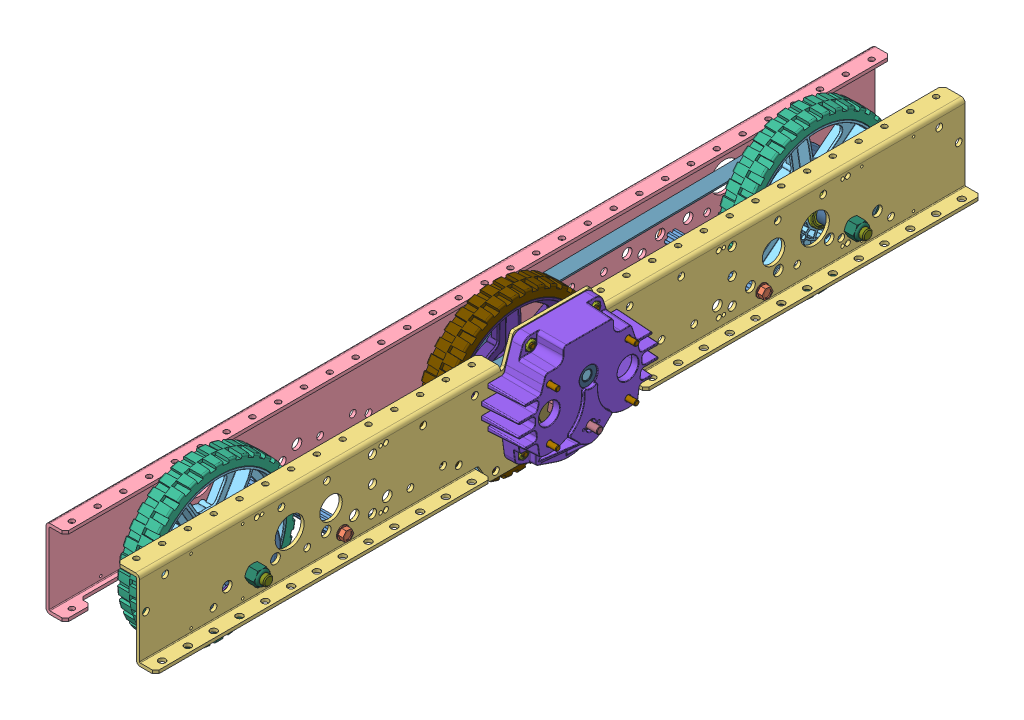
SolidWorks assembly AM14U3Long_Half, configuration Default. Lengths in mm.
Overall size (145.24 219.18 812.8).
91 component instances, 28 part files, 6 mates.
Components (placement in the parent):
- AM14U3Long_Frame_Half-1: AM14U3Long_Frame_Half [Default] at (0 136.144 -762.762) size (113.54 116.33 812.8)
  - 500Churro_3.375-2: 500Churro_3.375 [Default] at (-501.65 -66.929 562.737) x (0 0 1) z (-1 0 0) size (14.66 12.7 85.72)
  - 500Churro_3.375-4: 500Churro_3.375 [Default] at (-501.65 -66.929 149.987) x (0 0 1) z (-1 0 0) size (14.66 12.7 85.72)
  - ThreadRollingScrew_0.25-20x0.75_FHTS 0.25-20-G-0.75-C-1: ThreadRollingScrew_0.25-20x0.75_FHTS 0.25-20-G-0.75-C [Default] at (-498.475 -66.929 562.737) x (-1 0 0) z (0 0.924225 0.381849) size (24.64 12.19 12.19)
  - ThreadRollingScrew_0.25-20x0.75_FHTS 0.25-20-G-0.75-C-4: ThreadRollingScrew_0.25-20x0.75_FHTS 0.25-20-G-0.75-C [Default] at (-498.475 -66.929 149.987) x (-1 0 0) z (0 0.924225 0.381849) size (24.64 12.19 12.19)
  - ThreadRollingScrew_0.25-20x0.75_FHTS 0.25-20-G-0.75-C-5: ThreadRollingScrew_0.25-20x0.75_FHTS 0.25-20-G-0.75-C [Default] at (-590.55 -66.929 562.737) size (24.64 12.19 12.19)
  - ThreadRollingScrew_0.25-20x0.75_FHTS 0.25-20-G-0.75-C-7: ThreadRollingScrew_0.25-20x0.75_FHTS 0.25-20-G-0.75-C [Default] at (-590.55 -66.929 149.987) size (24.64 12.19 12.19)
  - AM14U3InnerPlate_Long-1: AM14U3InnerPlate_Long [Default] at (-501.65 -77.216 762.762) x (0 0 -1) z (0 -1 0) size (812.8 38.1 116.33)
  - AM14U3OuterPlate_Long_DefaultSM-FLAT-PATTERN-1: AM14U3OuterPlate_Long_DefaultSM-FLAT-PATTERN [Default] at (-587.375 -77.216 -50.038) x (0 0 1) z (0 -1 0) size (812.8 19.05 77.72)
- ToughboxMini-1: ToughboxMini [Default] at (-549.0167 66.1299 -315.2992) x (0 0.001296 0.999999) z (-1 0 0) size (140.05 118.73 142.29)
  - TBMiniSmallHexShaft-1: TBMiniSmallHexShaft [Default] at (-127.8104 29.3671 -52.3959) x (-0.59657 -0.802561 0) z (-0.802561 0.59657 0) size (11 38.23 9.52)
  - Bearing_FR6ZZ-1: Bearing_FR6ZZ [Default] at (-96.247 60.278 -52.5991) x (-0.893862 0.448342 0) z (0 0 1) size (24.69 24.69 7.16)
  - NylockNut_10-32-1: NylockNut_10-32 [Default] at (-129.8464 -8.0737 -56.3837) x (0.501678 0.865055 0) z (0 0 -1) size (9.53 11 5.96)
  - NylockNut_10-32-2: NylockNut_10-32 [Default] at (-59.2462 80.7349 -56.3837) x (0.999999 -0.001296 0) z (0 0 -1) size (9.53 11 5.96)
  - NylockNut_10-32-3: NylockNut_10-32 [Default] at (-122.7461 80.8172 -56.3837) x (0.500567 0.865698 0) z (0 0 -1) size (9.53 11 5.96)
  - NylockNut_10-32-4: NylockNut_10-32 [Default] at (-52.3764 -8.1741 -56.3837) x (-0.501678 -0.865055 0) z (0 0 -1) size (9.53 11 5.96)
  - TBMiniHousing-1: TBMiniHousing [Default] at (-91.0876 10.1882 -86.3557) x (0.999999 -0.001296 0) z (0 0 1) size (139.9 118.55 41.62)
  - Screw_SHCS_10-32x0.625-1: Screw_SHCS_10-32x0.625 [Default] at (-52.2832 63.7078 -74.4685) x (-0.564778 -0.825243 0) z (-0.825243 0.564778 0) size (7.82 20.65 7.82)
  - Screw_SHCS_10-32x0.625-2: Screw_SHCS_10-32x0.625 [Default] at (-122.7461 80.8172 -42.5915) x (0.507484 -0.861661 0) z (-0.861661 -0.507484 0) size (7.82 20.65 7.82)
  - Screw_SHCS_10-32x0.625-3: Screw_SHCS_10-32x0.625 [Default] at (-52.3764 -8.1741 -42.5915) x (0.507484 -0.861661 0) z (-0.861661 -0.507484 0) size (7.82 20.65 7.82)
  - Screw_SHCS_10-32x0.625-4: Screw_SHCS_10-32x0.625 [Default] at (-129.8464 -8.0737 -42.5915) x (0.507484 -0.861661 0) z (-0.861661 -0.507484 0) size (7.82 20.65 7.82)
  - Screw_SHCS_10-32x0.625-5: Screw_SHCS_10-32x0.625 [Default] at (-59.2462 80.7349 -42.5915) x (0.740711 -0.671824 0) z (-0.671824 -0.740711 0) size (7.82 20.65 7.82)
  - Screw_SHCS_10-32x0.625-6: Screw_SHCS_10-32x0.625 [Default] at (-52.3491 12.9079 -74.4685) x (-0.564778 -0.825243 0) z (-0.825243 0.564778 0) size (7.82 20.65 7.82)
  - Screw_SHCS_10-32x0.625-7: Screw_SHCS_10-32x0.625 [Default] at (-129.7532 63.8083 -74.4685) x (-0.966277 -0.257503 0) z (-0.257503 0.966277 0) size (7.82 20.65 7.82)
  - Screw_SHCS_10-32x0.625-8: Screw_SHCS_10-32x0.625 [Default] at (-129.819 13.0083 -74.4685) x (-0.99652 0.083357 0) z (0.083357 0.99652 0) size (7.82 20.65 7.82)
  - Bearing_R6ZZ-1: Bearing_R6ZZ [Default] at (-91.0349 50.9043 -84.8317) x (0.958138 -0.286306 0) z (0 0 1) size (22.23 22.23 7.11)
  - Bearing_R6ZZ-2: Bearing_R6ZZ [Default] at (-91.0876 10.1882 -84.8317) x (-0.661529 0.74992 0) z (0 0 1) size (22.23 22.23 7.11)
  - ExternalKlipring-1: ExternalKlipring [Default] at (-91.0876 10.1882 -64.4355) x (0.996411 -0.084651 0) z (0 0 1) size (19.07 20.96 1.27)
  - Bearing_Hex_FR8ZZ-1: Bearing_Hex_FR8ZZ [Default] at (-91.0876 10.1882 -44.6717) x (0.188693 -0.982036 0) z (0 0 -1) size (31.12 31.12 7.93)
  - TBMiniHexOutputShaft-1: TBMiniHexOutputShaft [Default] at (-100.2289 -30.5762 -52.3197) x (0.188693 -0.982036 0) z (-0.982036 -0.188693 0) size (14.66 142.29 12.7)
- Bearing_Hex_FR8ZZ-1: Bearing_Hex_FR8ZZ [Default] at (-593.7783 76.2 -406.4) x (0 0.32638 -0.945239) z (1 0 0) size (31.12 31.12 7.93)
- Belt_15mm_Long-1: Belt_15mm_Long [Default] at (-511.5261 79.756 -111.3496) x (0 -0.012051 -0.999927) z (0 0.999927 -0.012051) size (368.15 15 73.08)
- Belt_15mm_Long-2: Belt_15mm_Long [Default] at (-576.9127 76.2 -406.4) x (0 0.012051 -0.999927) z (0 -0.999927 -0.012051) size (368.15 15 73.08)
- NylockNut_0.375-16_91831A127-1: NylockNut_0.375-16_91831A127 [Default] at (-498.475 79.756 -701.4504) x (0 -1 0) z (0 0 1) size (14.29 12 16.5)
- NylockNut_0.375-16_91831A127-2: NylockNut_0.375-16_91831A127 [Default] at (-498.475 79.7563 -111.3496) x (0 -1 0) z (0 0 1) size (14.29 12 16.5)
- HHSBolt_0.375-16x4.25_HFBOLT 0.375-16x2.5x1-C-1: HHSBolt_0.375-16x4.25_HFBOLT 0.375-16x2.5x1-C [Default] at (-596.7222 79.756 -111.3496) size (114.12 16.48 14.27)
- HHSBolt_0.375-16x4.25_HFBOLT 0.375-16x2.5x1-C-2: HHSBolt_0.375-16x4.25_HFBOLT 0.375-16x2.5x1-C [Default] at (-596.7222 79.756 -701.4504) x (1 0 0) z (0 -0.203423 -0.979091) size (114.12 16.48 14.27)
- Wheel_6inHiGrip_Center-1: Wheel_6inHiGrip_Center [Default] at (-513.0653 208.3565 -483.6317) x (-1 0 0) z (0 -0.493281 0.86987) size (81.42 191.55 191.55)
  - Wheel_6inHiGrip-1: Wheel_6inHiGrip [Default] at (83.7987 67.439 110.9939) size (34.93 191.55 191.55)
    - Wheel_6inHiGrip_Wheel-1: Wheel_6inHiGrip_Wheel [Default] at (-52.6446 9.4231 21.378) size (34.93 132.08 132.08)
    - Wheel_6inHiGrip_Tread-1: Wheel_6inHiGrip_Tread [Default] at (-65.3446 9.4231 21.378) x (0 -0.304368 -0.952555) z (1 0 0) size (152.4 152.4 25.58)
  - HalfPulley_42t5mm-1: HalfPulley_42t5mm [Default] at (47.6006 76.862 132.3719) x (1 0 0) z (0 -0.5 0.866025) size (13 74.23 74.23)
  - HalfPulley_42t5mm-2: HalfPulley_42t5mm [Default] at (64.263 76.862 132.3719) x (-1 0 0) z (0 -0.499927 0.866067) size (13 74.23 74.23)
  - ThreadFormingScrew_10-24x1.25_93882A213-1: ThreadFormingScrew_10-24x1.25_93882A213 [Default] at (63.247 76.8605 108.5602) x (0 0.953802 -0.300437) z (1 0 0) size (10.52 10.52 35.59)
  - ThreadFormingScrew_10-24x1.25_93882A213-2: ThreadFormingScrew_10-24x1.25_93882A213 [Default] at (63.247 97.4833 120.4656) x (0 0.953802 -0.300437) z (1 0 0) size (10.52 10.52 35.59)
  - ThreadFormingScrew_10-24x1.25_93882A213-3: ThreadFormingScrew_10-24x1.25_93882A213 [Default] at (63.247 56.2398 144.2799) x (0 0.953802 -0.300437) z (1 0 0) size (10.52 10.52 35.59)
  - ThreadFormingScrew_10-24x1.25_93882A213-4: ThreadFormingScrew_10-24x1.25_93882A213 [Default] at (63.247 76.8625 156.1852) x (0 -0.013882 -0.999904) z (1 0 0) size (10.52 10.52 35.59)
  - ThreadFormingScrew_10-24x1.25_93882A213-5: ThreadFormingScrew_10-24x1.25_93882A213 [Default] at (63.247 97.4843 144.2781) x (0 -0.733065 -0.680158) z (1 0 0) size (10.52 10.52 35.59)
  - ThreadFormingScrew_10-24x1.25_93882A213-6: ThreadFormingScrew_10-24x1.25_93882A213 [Default] at (63.247 56.2388 120.4674) x (0 0.407306 -0.913292) z (1 0 0) size (10.52 10.52 35.59)
  - HalfPulley_42t5mm-3: HalfPulley_42t5mm [Default] at (-1.9548 76.862 132.3719) x (1 0 0) z (0 -1 -0.000063) size (13 74.23 74.23)
  - HalfPulley_42t5mm-4: HalfPulley_42t5mm [Default] at (14.7076 76.862 132.3719) x (-1 0 0) z (0 -1 0.000021) size (13 74.23 74.23)
  - HexHub_500EX-1: HexHub_500EX [Default] at (-8.3048 76.862 132.3719) x (0 -0.866025 -0.5) z (0 -0.5 0.866025) size (55.37 25.4 51.33)
  - ThreadFormingScrew_10-24x1.25_93882A213-7: ThreadFormingScrew_10-24x1.25_93882A213 [Default] at (-5.2568 97.4843 120.4656) x (0 -0.953802 0.300437) z (-1 0 0) size (10.52 10.52 35.59)
  - ThreadFormingScrew_10-24x1.25_93882A213-8: ThreadFormingScrew_10-24x1.25_93882A213 [Default] at (-5.2568 76.862 108.5594) x (0 -0.953802 0.300437) z (-1 0 0) size (10.52 10.52 35.59)
  - ThreadFormingScrew_10-24x1.25_93882A213-9: ThreadFormingScrew_10-24x1.25_93882A213 [Default] at (-5.2568 56.2398 120.4656) x (0 -0.953802 0.300437) z (-1 0 0) size (10.52 10.52 35.59)
  - ThreadFormingScrew_10-24x1.25_93882A213-10: ThreadFormingScrew_10-24x1.25_93882A213 [Default] at (-5.2568 97.4843 144.2781) x (0 -0.192002 -0.981394) z (-1 0 0) size (10.52 10.52 35.59)
  - ThreadFormingScrew_10-24x1.25_93882A213-11: ThreadFormingScrew_10-24x1.25_93882A213 [Default] at (-5.2568 56.2398 144.2781) x (0 -0.986288 0.16503) z (-1 0 0) size (10.52 10.52 35.59)
  - ThreadFormingScrew_10-24x1.25_93882A213-12: ThreadFormingScrew_10-24x1.25_93882A213 [Default] at (-5.2568 76.862 156.1844) x (0 -0.150217 -0.988653) z (-1 0 0) size (10.52 10.52 35.59)
  - Spacer_Hex_0.57x0.5-1: Spacer_Hex_0.57x0.5 [Default] at (57.8495 76.862 132.3719) x (0 -0.866025 -0.5) z (0 -0.5 0.866025) size (28.55 14.48 28.55)
- 6 HiGrip with bearings, pulleys and spacers-1: 6 HiGrip with bearings, pulleys and spacers [Default] at (-574.9579 3.6159 21.4388) x (1 0 0) z (0 0.865776 -0.500432) size (85.56 152.4 152.4)
  - 6 HiGrip Wheel Assembly Rev II-1: 6 HiGrip Wheel Assembly Rev II [Default] at (83.7987 67.439 110.9939) size (34.93 152.4 152.4)
    - 6 wheel Rev 4-1: 6 wheel Rev 4 [Default] at (-52.6446 9.4231 21.378) size (34.93 132.08 132.08)
    - 6 wheel tread II-1: 6 wheel tread II [Default] at (-65.3446 9.4231 21.378) x (0 0 -1) z (1 0 0) size (152.4 152.4 25.58)
  - HalfPulley_42t5mm-1: HalfPulley_42t5mm [Default] at (47.6006 76.862 132.3719) x (1 0 0) z (0 -0.5 0.866025) size (13 74.23 74.23)
  - HalfPulley_42t5mm-2: HalfPulley_42t5mm [Default] at (64.263 76.862 132.3719) x (-1 0 0) z (0 -0.499927 0.866067) size (13 74.23 74.23)
  - Bearing_1614ZZ-1: Bearing_1614ZZ [Default] at (62.612 76.862 132.3719) x (0 0.904908 -0.425608) z (-1 0 0) size (28.58 28.58 9.53)
  - Bearing_1614ZZ-2: Bearing_1614ZZ [Default] at (15.2791 76.862 132.3719) x (0 0.960548 -0.278115) z (1 0 0) size (28.58 28.58 9.53)
  - Washer_5-16-1: Washer_5-16 [Default] at (63.247 76.8605 108.5602) x (0 -0.624545 -0.780988) z (1 0 0) size (17.53 17.53 1.47)
  - Washer_5-16-2: Washer_5-16 [Default] at (63.247 97.4833 120.4656) x (0 -0.995817 0.091369) z (1 0 0) size (17.53 17.53 1.47)
  - Washer_5-16-3: Washer_5-16 [Default] at (63.247 56.2398 144.2799) x (0 0.546149 0.837688) z (1 0 0) size (17.53 17.53 1.47)
  - Washer_5-16-4: Washer_5-16 [Default] at (63.247 76.8625 156.1852) x (0 0.642695 -0.766122) z (1 0 0) size (17.53 17.53 1.47)
  - Washer_5-16-5: Washer_5-16 [Default] at (63.247 97.4843 144.2781) x (0 0.936259 -0.351311) z (1 0 0) size (17.53 17.53 1.47)
  - Washer_5-16-6: Washer_5-16 [Default] at (63.247 56.2388 120.4674) x (0 -0.160557 -0.987027) z (1 0 0) size (17.53 17.53 1.47)
  - Spacer_0.28x0.382-1: Spacer_0.28x0.382 [Default] at (74.4865 76.862 132.3719) x (0 -0.996837 -0.07947) z (-1 0 0) size (13.16 13.16 7.11)
  - Spacer_0.85x0.38-1: Spacer_0.85x0.38 [Default] at (-11.0734 76.862 132.3719) x (0 0.960548 -0.278115) z (1 0 0) size (19.05 19.05 21.59)
- 6 HiGrip with bearings, pulleys and spacers-2: 6 HiGrip with bearings, pulleys and spacers [Default] at (-513.4809 -62.9554 -646.1011) x (-1 0 0) z (0 0.624698 -0.780867) size (85.56 152.4 152.4)
  - 6 HiGrip Wheel Assembly Rev II-1: 6 HiGrip Wheel Assembly Rev II [Default] at (83.7987 67.439 110.9939) size (34.93 152.4 152.4)
    - 6 wheel Rev 4-1: 6 wheel Rev 4 [Default] at (-52.6446 9.4231 21.378) size (34.93 132.08 132.08)
    - 6 wheel tread II-1: 6 wheel tread II [Default] at (-65.3446 9.4231 21.378) x (0 0 -1) z (1 0 0) size (152.4 152.4 25.58)
  - HalfPulley_42t5mm-1: HalfPulley_42t5mm [Default] at (47.6006 76.862 132.3719) x (1 0 0) z (0 -0.5 0.866025) size (13 74.23 74.23)
  - HalfPulley_42t5mm-2: HalfPulley_42t5mm [Default] at (64.263 76.862 132.3719) x (-1 0 0) z (0 -0.499927 0.866067) size (13 74.23 74.23)
  - Bearing_1614ZZ-1: Bearing_1614ZZ [Default] at (62.612 76.862 132.3719) x (0 0.904908 -0.425608) z (-1 0 0) size (28.58 28.58 9.53)
  - Bearing_1614ZZ-2: Bearing_1614ZZ [Default] at (15.2791 76.862 132.3719) x (0 0.960548 -0.278115) z (1 0 0) size (28.58 28.58 9.53)
  - Washer_5-16-1: Washer_5-16 [Default] at (63.247 76.8605 108.5602) x (0 -0.624545 -0.780988) z (1 0 0) size (17.53 17.53 1.47)
  - Washer_5-16-2: Washer_5-16 [Default] at (63.247 97.4833 120.4656) x (0 -0.995817 0.091369) z (1 0 0) size (17.53 17.53 1.47)
  - Washer_5-16-3: Washer_5-16 [Default] at (63.247 56.2398 144.2799) x (0 0.546149 0.837688) z (1 0 0) size (17.53 17.53 1.47)
  - Washer_5-16-4: Washer_5-16 [Default] at (63.247 76.8625 156.1852) x (0 0.642695 -0.766122) z (1 0 0) size (17.53 17.53 1.47)
  - Washer_5-16-5: Washer_5-16 [Default] at (63.247 97.4843 144.2781) x (0 0.936259 -0.351311) z (1 0 0) size (17.53 17.53 1.47)
  - Washer_5-16-6: Washer_5-16 [Default] at (63.247 56.2388 120.4674) x (0 -0.160557 -0.987027) z (1 0 0) size (17.53 17.53 1.47)
  - Spacer_0.28x0.382-1: Spacer_0.28x0.382 [Default] at (74.4865 76.862 132.3719) x (0 -0.996837 -0.07947) z (-1 0 0) size (13.16 13.16 7.11)
  - Spacer_0.85x0.38-1: Spacer_0.85x0.38 [Default] at (-11.0734 76.862 132.3719) x (0 0.960548 -0.278115) z (1 0 0) size (19.05 19.05 21.59)
Mates (geometry in assembly coordinates):
- Concentric1: concentric anti-aligned: cylinder of HHSBolt_0.375-16x4.25_HFBOLT 0.375-16x2.5x1-C-1 through (-596.7222 79.756 -111.3496) axis (-1 0 0) radius 4.7625; cylinder of 6 HiGrip with bearings, pulleys and spacers-1/Spacer_0.28x0.382-1 through (-507.5834 79.756 -111.3496) axis (1 0 0) radius 4.8514
- Concentric2: concentric anti-aligned: cylinder of HHSBolt_0.375-16x4.25_HFBOLT 0.375-16x2.5x1-C-2 through (-596.7222 79.756 -701.4504) axis (-1 0 0) radius 4.7625; cylinder of 6 HiGrip with bearings, pulleys and spacers-2/Spacer_0.85x0.38-1 through (-523.9975 79.756 -701.4504) axis (1 0 0) radius 4.826
- Coincident1: coincident aligned: axis of Belt_15mm_Long-2 through (-561.9127 76.2 -406.4) axis (-1 0 0); axis of Wheel_6inHiGrip_Center-1/HalfPulley_42t5mm-2 through (-558.4587 76.2 -406.4) axis (-1 0 0)
- Width1: width anti-aligned: plane of Belt_15mm_Long-2 through (-561.9127 76.2 -406.4) normal (1 0 0); plane of Belt_15mm_Long-2 through (-576.9127 76.2 -406.4) normal (-1 0 0); plane of 6 HiGrip with bearings, pulleys and spacers-2/HalfPulley_42t5mm-2 through (-580.2839 47.6626 -706.3412) normal (-1 0 0); plane of 6 HiGrip with bearings, pulleys and spacers-2/HalfPulley_42t5mm-1 through (-558.5415 111.8498 -696.5623) normal (1 0 0)
- Width2: width anti-aligned: plane of Belt_15mm_Long-1 through (-511.5261 79.756 -111.3496) normal (1 0 0); plane of Belt_15mm_Long-2 through (-576.9127 76.2 -406.4) normal (-1 0 0); plane of Wheel_6inHiGrip_Center-1/HalfPulley_42t5mm-2 through (-579.8683 108.663 -406.6486) normal (-1 0 0); plane of Wheel_6inHiGrip_Center-1/HalfPulley_42t5mm-3 through (-508.5705 60.1879 -378.1596) normal (1 0 0)
- Width3: width anti-aligned: plane of Belt_15mm_Long-1 through (-526.5261 79.756 -111.3496) normal (-1 0 0); plane of Belt_15mm_Long-1 through (-511.5261 79.756 -111.3496) normal (1 0 0); plane of 6 HiGrip with bearings, pulleys and spacers-1/HalfPulley_42t5mm-2 through (-508.1549 79.7749 -78.8857) normal (1 0 0); plane of 6 HiGrip with bearings, pulleys and spacers-1/HalfPulley_42t5mm-1 through (-529.8973 79.7398 -143.8135) normal (-1 0 0)
